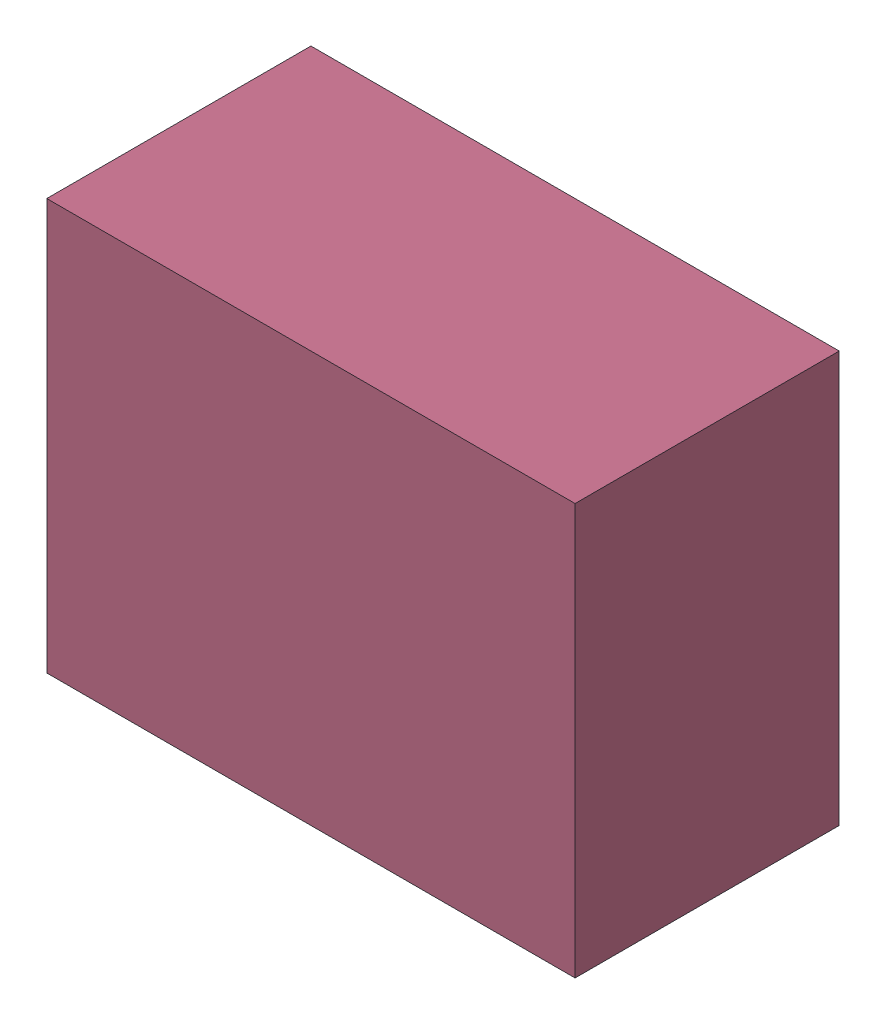
SolidWorks assembly LED2Kanaloa_v2.0.0_GPIO_b, configuration Default. Lengths in mm.
Overall size (3.6 2.8 1.8).
8 component instances, 3 part files, 0 mates.
Components (placement in the parent):
- 352877648-1: 352877648 [Default] at (91.329 28.702 0) size (0.38 1.3 0.85)
  - Extruded_14-1: Extruded_14 [Default] at origin size (0.38 1.3 0.85)
- 352877904-1: 352877904 [Default] at (92.329 28.702 0) size (2.2 1.27 0.85)
  - Extruded_18-1: Extruded_18 [Default] at origin size (2.2 1.27 0.85)
- 352877648-2: 352877648 [Default] at (93.329 28.702 0) size (0.38 1.3 0.85)
  - Extruded_14-1: Extruded_14 [Default] at origin size (0.38 1.3 0.85)
- 352878544-1: 352878544 [Default] at (92.329 28.702 0) size (3.6 2.8 1.8)
  - Extruded_6-1: Extruded_6 [Default] at origin size (3.6 2.8 1.8)
